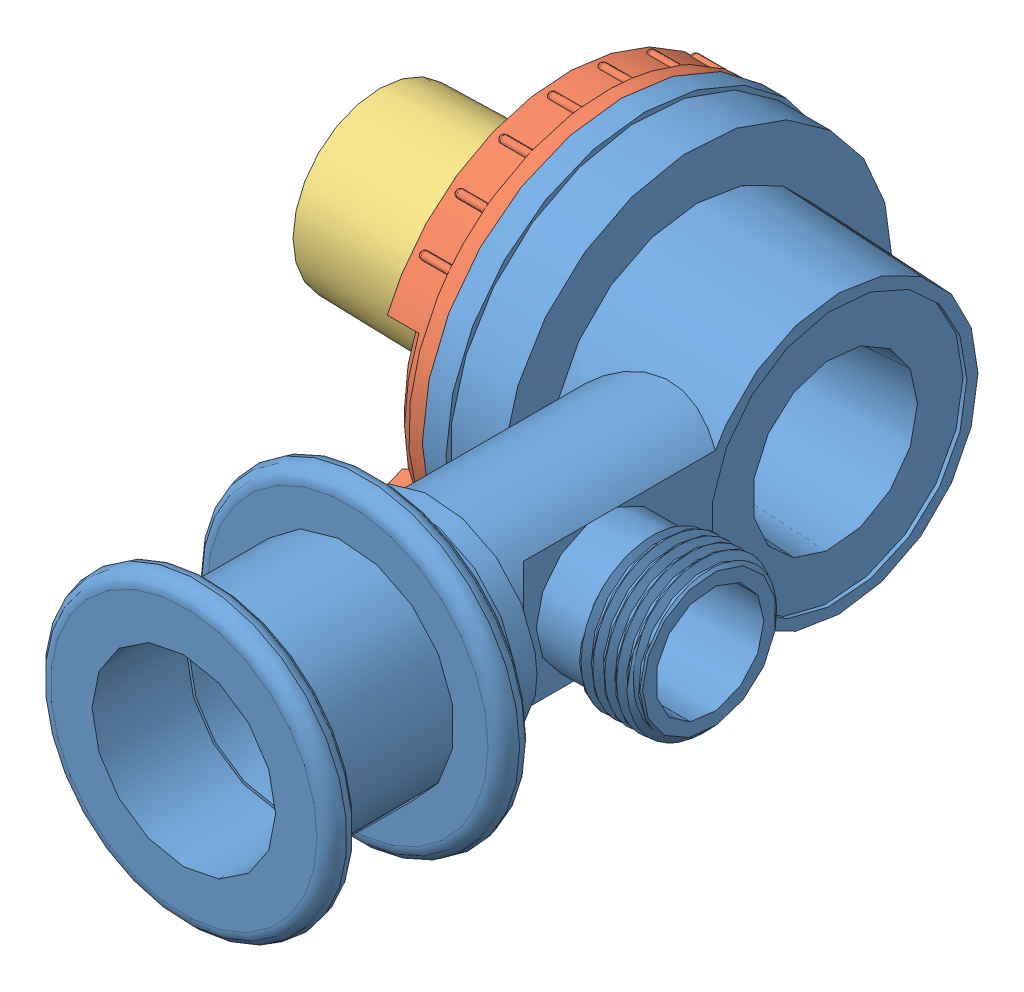
SolidWorks assembly Assy_Ambu-Bag_Outlet, configuration Default. Lengths in mm.
Overall size (72.2 65.3 107.95).
5 component instances, 5 part files, 9 mates.
Components (placement in the parent):
- Ambu-Bag_Outlet-1: Ambu-Bag_Outlet [Default] at origin size (42.06 50.5 100.55)
- Ambu-Bag_Outlet_Body_Connector-1: Ambu-Bag_Outlet_Body_Connector [Default] x (-1 0 0) z (0 -0.924225 -0.381849) size (13 50 50)
- Ambu-Bag_Outlet_Body_Connector_Pipe-1: Ambu-Bag_Outlet_Body_Connector_Pipe [Default] at (-36.15 0 0) size (35 30 30)
- Ambu-Bag_Outlet_Clip-1: Ambu-Bag_Outlet_Clip [Default] at (-13.5 0 0) x (1 0 0) z (0 -0.381849 0.924225) size (5 30.5 30.5)
- Ambu-Bag_Outlet_Diaphram-1: Ambu-Bag_Outlet_Diaphram [Default] at (2.6 0 0) x (-1 0 0) z (0 -1 0) size (16 43.5 43.5)
Mates (geometry in assembly coordinates):
- Coincident1: coincident: plane of assembly; plane of assembly; plane of Ambu-Bag_Outlet-1 through (-5.5 23 0) normal (-1 0 0); plane of Ambu-Bag_Outlet_Body_Connector-1 through (-5.5 8.9735 -21.7193) normal (1 0 0)
- Concentric1: concentric: circle of assembly; cylinder of assembly; circle of Ambu-Bag_Outlet-1; cylinder of Ambu-Bag_Outlet_Body_Connector-1 through (0 0 0) axis (1 0 0) radius 12.5
- Coincident2: coincident: plane of assembly; plane of assembly; plane of Ambu-Bag_Outlet_Body_Connector-1 through (-6.25 7.8852 -19.0852) normal (1 0 0); plane of Ambu-Bag_Outlet_Body_Connector_Pipe-1 through (-6.25 15 0) normal (-1 0 0)
- Concentric2: concentric: cylinder of assembly; circle of assembly; cylinder of Ambu-Bag_Outlet_Body_Connector-1 through (0 0 0) axis (1 0 0) radius 12.5; circle of Ambu-Bag_Outlet_Body_Connector_Pipe-1
- Coincident3: coincident: plane of assembly; plane of assembly; plane of Ambu-Bag_Outlet_Body_Connector-1 through (-8.5 7.7324 -18.7155) normal (-1 0 0); plane of Ambu-Bag_Outlet_Clip-1 through (-8.5 12.4936 5.1618) normal (1 0 0)
- Concentric3: concentric: circle of assembly; cylinder of assembly; circle of Ambu-Bag_Outlet_Body_Connector_Pipe-1; cylinder of Ambu-Bag_Outlet_Clip-1 through (-13.5 0 0) axis (-1 0 0) radius 11.5
- Angle1: planar angle = 1.570796 rad: plane of assembly through (0 0 0) normal (0 1 0); plane of Ambu-Bag_Outlet_Diaphram-1 through (2.6 0 0) normal (0 0 -1); plane of assembly
- Concentric5: concentric: cylinder of assembly; cylinder of assembly; cylinder of Ambu-Bag_Outlet-1 through (-1 0 0) axis (1 0 0) radius 17.0794; cylinder of Ambu-Bag_Outlet_Diaphram-1 through (2.6 0 0) axis (1 0 0) radius 19.05
- Coincident5: coincident: plane of assembly; plane of assembly; plane of Ambu-Bag_Outlet-1 through (2.6 18.75 0) normal (-1 0 0); plane of Ambu-Bag_Outlet_Diaphram-1 through (2.6 0 -18.75) normal (1 0 0)
